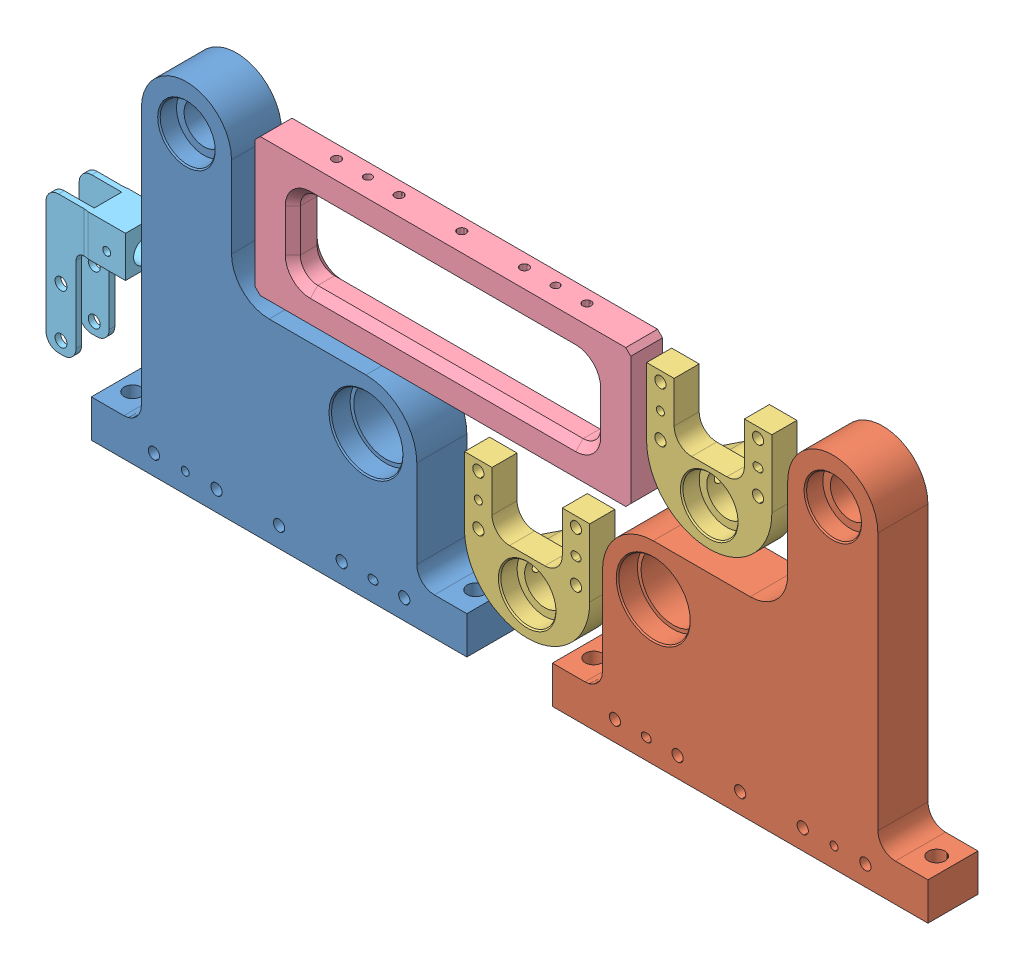
SolidWorks assembly Assem1, configuration Default. Lengths in mm.
Overall size (352.52 143 20).
6 component instances, 5 part files, 13 mates.
Components (placement in the parent):
- LAS-03-0005-1: LAS-03-0005 [Default] at (-51.2896 -65.2304 13.2809) size (150 143 20)
- LAS-03-0004-1: LAS-03-0004 [Default] at (206.8787 -65.2304 13.2809) x (-1 0 0) z (0 0 -1) size (150 143 20)
- LAS-02-0002-1: LAS-02-0002 [Default] at (84.7987 -31.6217 13.2809) x (-1 0 0) z (0 0 -1) size (50 52 20)
- LAS-03-0002-1: LAS-03-0002 [Default] at (51.1787 46.0571 0.5809) x (0 1 0) z (0 0 1) size (55 150 12.7)
- LAS-02-0002-2: LAS-02-0002 [Default] at (157.5287 35.5531 13.2809) x (-1 0 0) z (0 0 -1) size (50 52 20)
- LAS-01-0008-1: LAS-01-0008 [Default] at (-75.6396 3.1657 5.2809) x (0 0 1) z (-1 0 0) size (16 55 32)
Mates (geometry in assembly coordinates):
- Parallel1: parallel aligned: plane of LAS-03-0005-1 through (-89.2896 -65.2304 -6.7191) normal (0 -1 0); plane of LAS-03-0004-1 through (244.8787 -65.2304 -6.7191) normal (0 -1 0)
- Coincident2: coincident aligned: plane of LAS-03-0004-1 through (206.8787 59.7696 13.2809) normal (0 0 1); plane of LAS-02-0002-1 through (84.7987 -31.6217 13.2809) normal (0 0 1)
- Coincident3: coincident aligned: plane of LAS-03-0005-1 through (-51.2896 59.7696 13.2809) normal (0 0 1); plane of LAS-03-0004-1 through (206.8787 59.7696 13.2809) normal (0 0 1)
- Coincident4: coincident aligned: plane of LAS-03-0005-1 through (-89.2896 -65.2304 -6.7191) normal (0 -1 0); plane of LAS-03-0004-1 through (244.8787 -65.2304 -6.7191) normal (0 -1 0)
- Distance5: distance = 5.08 mm anti-aligned: plane of LAS-03-0004-1 through (114.8787 0.9338 -6.7191) normal (-1 0 0); plane of LAS-02-0002-1 through (109.7987 -46.6217 -6.7191) normal (1 0 0)
- Distance7: distance = 6.35 mm anti-aligned: plane of LAS-03-0002-1 through (126.1787 18.5571 13.2809) normal (0 -1 0); plane of LAS-03-0004-1 through (173.8787 12.2071 13.2809) normal (0 1 0)
- Coincident6: coincident aligned: plane of LAS-03-0004-1 through (206.8787 59.7696 13.2809) normal (0 0 1); plane of LAS-03-0002-1 through (51.1787 46.0571 13.2809) normal (0 0 1)
- Coincident7: coincident aligned: plane of LAS-03-0004-1 through (206.8787 59.7696 13.2809) normal (0 0 1); plane of LAS-02-0002-2 through (157.5287 35.5531 13.2809) normal (0 0 1)
- Distance8: distance = 6.35 mm anti-aligned: plane of LAS-03-0004-1 through (188.8787 59.7696 13.2809) normal (-1 0 0); plane of LAS-02-0002-2 through (182.5287 20.5531 -6.7191) normal (1 0 0)
- Distance9: distance = 6.35 mm anti-aligned: plane of LAS-02-0002-2 through (132.5287 20.5531 -6.7191) normal (-1 0 0); plane of LAS-03-0002-1 through (126.1787 18.5571 13.2809) normal (1 0 0)
- Distance11: distance = 6.35 mm: line of LAS-03-0002-1 through (-23.8213 20.5571 0.5809) axis (0 0 1); cylinder of LAS-03-0005-1 through (-18.2896 27.2071 13.2809) axis (0 0 -1) radius 15
- Coincident9: coincident aligned: plane of LAS-03-0002-1 through (51.1787 46.0571 13.2809) normal (0 0 1); plane of LAS-01-0008-1 through (-107.6396 -41.8343 13.2809) normal (0 0 1)
- Distance12: distance = 6.35 mm anti-aligned: plane of LAS-03-0005-1 through (-69.2896 0.9338 -6.7191) normal (-1 0 0); plane of LAS-01-0008-1 through (-75.6396 3.1657 5.2809) normal (1 0 0)
